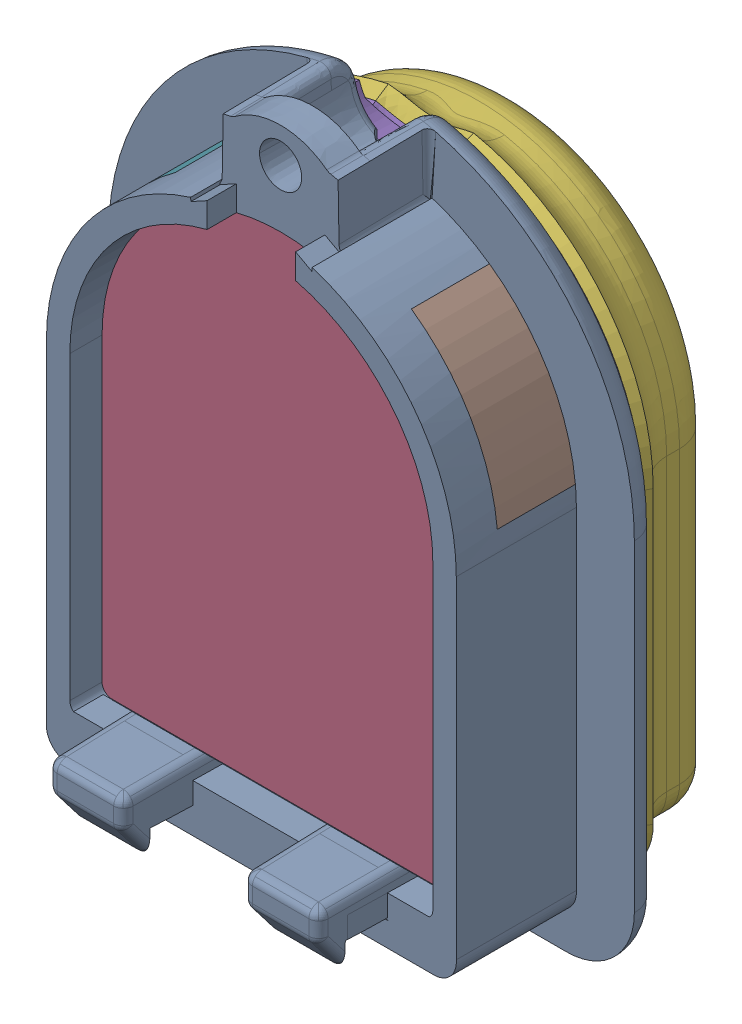
SolidWorks assembly Conti_PinDesign, configuration 默认. Lengths in mm.
Overall size (26.95 34.26 17.16).
10 component instances, 8 part files, 21 mates.
Components (placement in the parent):
- IntegratedOriginalTip1-1: IntegratedOriginalTip1 [默认] at (-1.9035 7.7463 -5.5591) size (26.95 34.26 11.2)
- IntegratedOriginallensnew-1: IntegratedOriginallensnew [默认] at (-1.9035 7.7463 -5.5591) size (18.6 25.2 6)
- IntegratedOriginalSkin0.2-1: IntegratedOriginalSkin0.2 [默认] at (-1.9035 7.4963 -5.5591) x (-1 0 0) z (0 0 -1) size (23.9 30.06 5.2)
- IntegratedOriginalSkin1-1: IntegratedOriginalSkin1 [默认] at (-1.9035 7.4963 -5.5591) x (-1 0 0) z (0 0 -1) size (22.77 29.32 5.25)
- IntegratedOriginalsidelens1-1: IntegratedOriginalsidelens1 [默认] at (-1.9035 7.7463 -6.2091) size (6.4 7.71 4)
- IntegratedOriginalsidelens1-2: IntegratedOriginalsidelens1 [默认] at (-1.9035 7.7463 2.0909) x (-1 0 0) z (0 0 -1) size (6.4 7.71 4)
- IntegratedOriginalbottomlens-1: IntegratedOriginalbottomlens [默认] at (-5.9035 -10.5037 0.4409) x (1 0 0) z (0 1 0) size (8 4.5 2.35)
- 装配体1-1: 装配体1 [默认] at (-2.3094 2.4986 -10.5591) x (-1 0 0) z (0 0 -1) size (15.5 20.5 2.3)
  - ConMarker-1: ConMarker [默认] at (-7.6559 -7.9983 -0.2) size (15.5 20.5 0.4)
  - 零件1-1: 零件1 [默认] at (-7.9059 -7.7483 -1.3) size (15.45 20.45 2.3)
Mates (geometry in assembly coordinates):
- 同心1: concentric aligned: cylinder of Tip1-1 through (-1.9035 7.7463 51.2878) axis (0 0 -1) radius 9.3; cylinder of lensnew-1 through (-1.9035 7.7463 0.4409) axis (0 0 -1) radius 9.3
- 重合1: coincident anti-aligned: plane of Tip1-1 through (-1.9035 -8.1537 51.2878) normal (0 1 0); plane of lensnew-1 through (-11.2035 -8.1537 0.4409) normal (0 -1 0)
- 重合2: coincident aligned: plane of Tip1-1 through (-1.964 4.3089 -5.5591) normal (0 0 -1); plane of lensnew-1 through (-1.9035 7.7463 -5.5591) normal (0 0 -1)
- 重合3: coincident anti-aligned: plane of lensnew-1 through (-1.9035 7.7463 -5.5591) normal (0 0 -1); plane of IntegratedOriginalSkin0.2-1 through (-1.9035 7.4963 -5.5591) normal (0 0 1)
- 同心2: concentric aligned: cone of Tip1-1 through (-1.9035 19.9963 -1.0591) axis (0 0 1); cylinder of IntegratedOriginalSkin0.2-1 through (-1.9035 19.9963 -6.3091) axis (0 0 1) radius 2.75
- 宽度1: width aligned: plane of IntegratedOriginalSkin0.2-1 through (-13.8535 7.4963 -5.5591) normal (-1 0 0); plane of IntegratedOriginalSkin0.2-1 through (10.0465 7.4963 -5.5591) normal (1 0 0); plane of Tip1-1 through (-12.4035 7.7463 2.0909) normal (-1 0 0); plane of Tip1-1 through (8.5965 7.7463 2.0909) normal (1 0 0)
- 重合4: coincident anti-aligned: plane of IntegratedOriginalSkin0.2-1 through (-1.9035 7.4963 -10.7591) normal (0 0 -1); plane of IntegratedOriginalSkin1-1 through (-1.9035 7.4963 -10.7591) normal (0 0 1)
- 宽度2: width anti-aligned: plane of IntegratedOriginalSkin0.2-1 through (-13.8535 7.4963 -5.5591) normal (-1 0 0); plane of IntegratedOriginalSkin0.2-1 through (10.0465 7.4963 -5.5591) normal (1 0 0); plane of IntegratedOriginalSkin1-1 through (-12.8325 0.0508 -6.2245) normal (-0.891007 0 0.45399); plane of IntegratedOriginalSkin1-1 through (9.0255 0.0508 -6.2245) normal (0.891007 0 0.45399)
- 重合5: coincident aligned: cone of IntegratedOriginalSkin0.2-1 through (-1.9035 7.4963 -6.2245) axis (0 0 1); cone of IntegratedOriginalSkin1-1 through (-1.9035 7.4963 -6.2245) axis (0 0 1)
- 重合6: coincident anti-aligned: plane of Tip1-1 through (-16.7251 9.2061 -4.0591) normal (0.104528 0.994522 0); plane of sidelens1-1 through (8.4147 6.5638 -0.0591) normal (-0.104528 -0.994522 0)
- 重合7: coincident anti-aligned: plane of Tip1-1 through (-1.9035 7.7463 -4.0591) normal (0 0 1); plane of sidelens1-1 through (8.4147 6.5638 -4.0591) normal (0 0 -1)
- 同心3: concentric aligned: cylinder of Tip1-1 through (-1.9035 7.7463 2.0909) axis (0 0 -1) radius 10.5; cylinder of sidelens1-1 through (-1.9035 7.7463 -0.0591) axis (0 0 -1) radius 10.5
- 同心4: concentric anti-aligned: cylinder of Tip1-1 through (-1.9035 7.7463 2.0909) axis (0 0 -1) radius 10.5; cylinder of sidelens1-2 through (-1.9035 7.7463 -4.0591) axis (0 0 1) radius 10.5
- 重合8: coincident anti-aligned: plane of Tip1-1 through (12.0819 17.1622 -0.0591) normal (0.104528 -0.994522 0); plane of sidelens1-2 through (-13.0579 14.5199 -4.0591) normal (-0.104528 0.994522 0)
- 重合9: coincident anti-aligned: plane of Tip1-1 through (-1.9035 7.7463 -4.0591) normal (0 0 1); plane of sidelens1-2 through (-1.9035 7.7463 -4.0591) normal (0 0 -1)
- 重合10: coincident anti-aligned: plane of lensnew-1 through (-11.2035 -8.1537 0.4409) normal (0 -1 0); plane of bottomlens-1 through (-5.9035 -8.1537 0.4409) normal (0 1 0)
- 重合11: coincident anti-aligned: plane of Tip1-1 through (-5.9035 -18.1537 0.4409) normal (0 0 -1); plane of bottomlens-1 through (-5.9035 -8.1537 0.4409) normal (0 0 1)
- 重合12: coincident anti-aligned: plane of Tip1-1 through (2.0965 -18.1537 0.4409) normal (-1 0 0); plane of bottomlens-1 through (2.0965 -8.1537 0.4409) normal (1 0 0)
- 重合13: coincident aligned: plane of IntegratedOriginalSkin0.2-1 through (-1.9035 7.4963 -10.7591) normal (0 0 -1); plane of 装配体1-1/ConMarker-1 through (5.3465 -5.4997 -10.7591) normal (0 0 -1)
- 宽度3: width aligned: plane of IntegratedOriginalTip1-1 through (8.5965 7.7463 2.0909) normal (1 0 0); plane of IntegratedOriginalTip1-1 through (-12.4035 7.7463 2.0909) normal (-1 0 0); plane of 装配体1-1/ConMarker-1 through (5.8465 5.4854 -10.3591) normal (1 0 0); plane of 装配体1-1/ConMarker-1 through (-9.6535 -5.4997 -10.7591) normal (-1 0 0)
- 距离1: distance = 5 mm aligned: plane of IntegratedOriginalTip1-1 through (-1.9035 -10.4997 2.0909) normal (0 -1 0); plane of 装配体1-1/ConMarker-1 through (5.3465 -5.4997 -10.7591) normal (0 -1 0)
